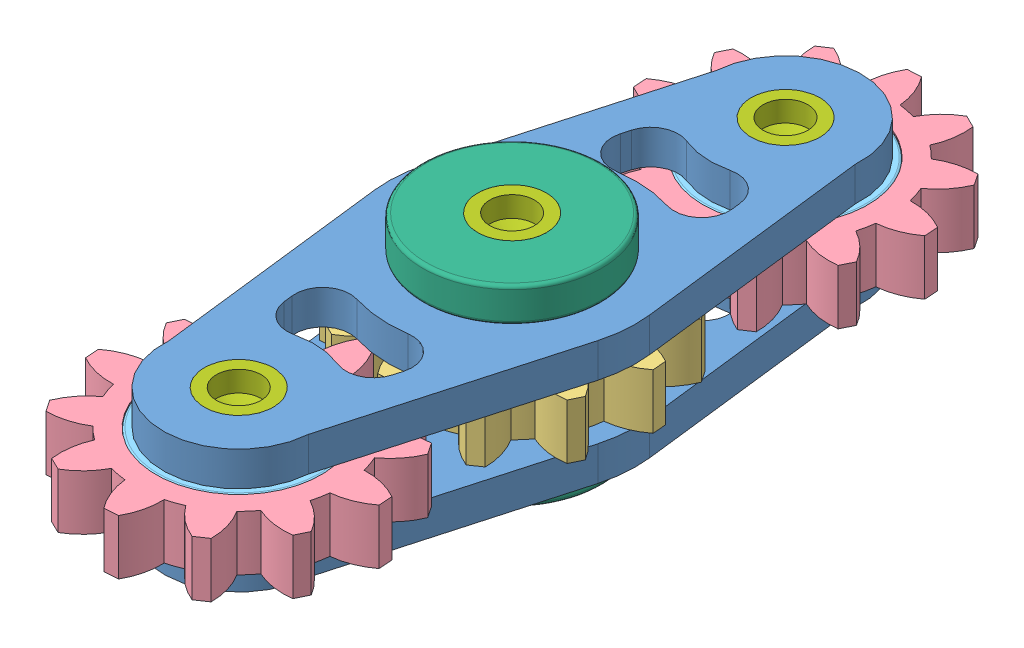
SolidWorks assembly gear fidget spinner, configuration Default. Lengths in mm.
Overall size (59.32 28 127.34).
14 component instances, 7 part files, 22 mates.
Components (placement in the parent):
- top cover for fidget spinner-1: top cover for fidget spinner [Default] at (38.5001 48.0006 73.7064) x (0.077744 0 -0.996973) z (0.996973 0 0.077744) size (96 5 36)
- angular contact ball bearing_68_iso-1: angular contact ball bearing_68_iso [ISO 15 ABB - 828 - Full,DE,AC,Full_68] at (38.5001 48.0006 73.7064) x (0 1 0) z (-0.648692 0 0.761051) size (5.28 24 24)
- gear 2 for fidget spinner-1: gear 2 for fidget spinner [Default] at (38.5001 54.5006 73.7064) x (-0.43516 0 0.900353) z (-0.900353 0 -0.43516) size (40 8 40)
- gear1 for fidget spinner-1: gear1 for fidget spinner [Default] at (35.6235 54.5006 110.5945) x (0.898762 0 0.438436) z (-0.438436 0 0.898762) size (40 8 40)
- gear1 for fidget spinner-2: gear1 for fidget spinner [Default] at (41.3766 54.5006 36.8184) x (-0.895115 0 -0.445835) z (0.445835 0 -0.895115) size (40 8 40)
- instrument ball bearing_68_am-1: instrument ball bearing_68_am [AFBMA 12.1.4.1 - 0080-24 - Full,DE,AC,Full_68] at (35.6235 54.5006 110.5945) x (0 -1 0) z (0 0 1) size (8 24 24)
- instrument ball bearing_68_am-2: instrument ball bearing_68_am [AFBMA 12.1.4.1 - 0080-24 - Full,DE,AC,Full_68] at (41.3766 54.5006 36.8184) x (0 -1 0) z (0 0 1) size (8 24 24)
- top cover for fidget spinner-2: top cover for fidget spinner [Default] at (38.5001 61.0006 73.7064) x (0.077744 0 -0.996973) z (-0.996973 0 -0.077744) size (96 5 36)
- angular contact ball bearing_68_iso-2: angular contact ball bearing_68_iso [ISO 15 ABB - 828 - Full,DE,AC,Full_68] at (38.5001 61.0006 73.7064) x (0 -1 0) z (0.648692 0 -0.761051) size (5.28 24 24)
- top seal for fidget spinner-1: top seal for fidget spinner [Default] at (38.5001 63.5006 73.7064) x (-0.870311 0 0.492503) z (-0.492503 0 -0.870311) size (26 5 26)
- top seal for fidget spinner-2: top seal for fidget spinner [Default] at (38.5001 45.5006 73.7064) x (-0.870311 0 0.492503) z (0.492503 0 0.870311) size (26 5 26)
- rivet 11_din-1: rivet 11_din [DIN 7341-A8x20-St-AC-18] at (41.3766 54.5006 36.8184) x (0 -1 0) z (0.716327 0 -0.697765) size (18 10 10)
- rivet 11_din-2: rivet 11_din [DIN 7341-A8x20-St-AC-18] at (35.6235 54.5006 110.5945) x (0 -1 0) z (0 0 1) size (18 10 10)
- rivet 11_din-3: rivet 11_din [DIN 7341-A8x30-St-AC-28] at (38.5001 54.5006 73.7064) x (0 -1 0) z (0 0 1) size (28 10 10)
Mates (geometry in assembly coordinates):
- Coincident1: coincident aligned: plane of top cover for fidget spinner-1 through (38.5001 50.5006 73.7064) normal (0 1 0); plane of angular contact ball bearing_68_iso-1 through (29.5958 50.5006 66.1167) normal (0 1 0)
- Concentric3: concentric aligned: circle of angular contact ball bearing_68_iso-1; circle of gear 2 for fidget spinner-1
- Coincident3: coincident anti-aligned: plane of top cover for fidget spinner-1 through (38.5001 50.5006 73.7064) normal (0 1 0); plane of gear 2 for fidget spinner-1 through (48.3271 50.5006 86.5865) normal (0 -1 0)
- Concentric4: concentric aligned: cylinder of top cover for fidget spinner-1 through (35.6235 50.5006 110.5945) axis (0 -1 0) radius 4; cylinder of gear1 for fidget spinner-1 through (35.6235 58.5006 110.5945) axis (0 -1 0) radius 12
- Coincident4: coincident anti-aligned: plane of top cover for fidget spinner-1 through (38.5001 50.5006 73.7064) normal (0 1 0); plane of gear1 for fidget spinner-1 through (48.5393 50.5006 100.8144) normal (0 -1 0)
- Concentric5: concentric aligned: cylinder of top cover for fidget spinner-1 through (41.3766 50.5006 36.8184) axis (0 -1 0) radius 4; cylinder of gear1 for fidget spinner-2 through (41.3766 58.5006 36.8184) axis (0 -1 0) radius 12
- Coincident5: coincident anti-aligned: plane of top cover for fidget spinner-1 through (38.5001 50.5006 73.7064) normal (0 1 0); plane of gear1 for fidget spinner-2 through (28.3806 50.5006 46.4916) normal (0 -1 0)
- Concentric6: concentric aligned: cylinder of gear1 for fidget spinner-1 through (35.6235 58.5006 110.5945) axis (0 -1 0) radius 12; cylinder of instrument ball bearing_68_am-1 through (35.6235 75.1381 110.5945) axis (0 -1 0) radius 4
- Concentric7: concentric aligned: cylinder of gear1 for fidget spinner-2 through (41.3766 58.5006 36.8184) axis (0 -1 0) radius 12; cylinder of instrument ball bearing_68_am-2 through (41.3766 75.1381 36.8184) axis (0 -1 0) radius 4
- Coincident6: coincident aligned: plane of gear1 for fidget spinner-1 through (48.5393 58.5006 100.8144) normal (0 1 0); plane of instrument ball bearing_68_am-1 through (45.2235 58.5006 110.5945) normal (0 1 0)
- Coincident7: coincident aligned: plane of gear1 for fidget spinner-2 through (28.3806 58.5006 46.4916) normal (0 1 0); plane of instrument ball bearing_68_am-2 through (50.9766 58.5006 36.8184) normal (0 1 0)
- Concentric8: concentric anti-aligned: cylinder of top cover for fidget spinner-1 through (38.5001 50.5006 73.7064) axis (0 -1 0) radius 12; cylinder of angular contact ball bearing_68_iso-1 through (38.5001 27.3631 73.7064) axis (0 1 0) radius 12
- GearMate5: gear = 30 : 30 mm: line of gear 2 for fidget spinner-1 through (38.5001 58.5006 73.7064) axis (0 -1 0); line of gear1 for fidget spinner-2 through (41.3766 58.5006 36.8184) axis (0 -1 0)
- GearMate6: gear = 30 : 30 mm: line of gear 2 for fidget spinner-1 through (38.5001 58.5006 73.7064) axis (0 -1 0); line of gear1 for fidget spinner-1 through (35.6235 58.5006 110.5945) axis (0 -1 0)
- Concentric9: concentric aligned: cylinder of angular contact ball bearing_68_iso-2 through (38.5001 81.6381 73.7064) axis (0 -1 0) radius 4; cylinder of top seal for fidget spinner-1 through (38.5001 68.5006 73.7064) axis (0 -1 0) radius 4
- Coincident10: coincident anti-aligned: plane of angular contact ball bearing_68_iso-2 through (30.6042 63.5006 66.9763) normal (0 1 0); plane of top seal for fidget spinner-1 through (38.5001 63.5006 73.7064) normal (0 -1 0)
- Concentric10: concentric aligned: cylinder of top cover for fidget spinner-2 through (41.3766 58.5006 36.8184) axis (0 1 0) radius 4; cylinder of rivet 11_din-1 through (41.3766 84.5006 36.8184) axis (0 1 0) radius 4
- Concentric11: concentric aligned: cylinder of top cover for fidget spinner-2 through (35.6235 58.5006 110.5945) axis (0 1 0) radius 4; cylinder of rivet 11_din-2 through (35.6235 84.5006 110.5945) axis (0 1 0) radius 4
- Coincident11: coincident aligned: plane of top cover for fidget spinner-2 through (38.5001 63.5006 73.7064) normal (0 1 0); plane of rivet 11_din-1 through (41.3766 63.5006 36.8184) normal (0 1 0)
- Coincident12: coincident anti-aligned: plane of top cover for fidget spinner-2 through (38.5001 63.5006 73.7064) normal (0 1 0); circle of rivet 11_din-2
- Concentric12: concentric anti-aligned: cylinder of top seal for fidget spinner-1 through (38.5001 68.5006 73.7064) axis (0 -1 0) radius 4; cylinder of rivet 11_din-3 through (38.5001 76.5006 73.7064) axis (0 1 0) radius 3.25
- Coincident13: coincident aligned: plane of top seal for fidget spinner-1 through (38.5001 68.5006 73.7064) normal (0 1 0); plane of rivet 11_din-3 through (38.5001 68.5006 73.7064) normal (0 1 0)
